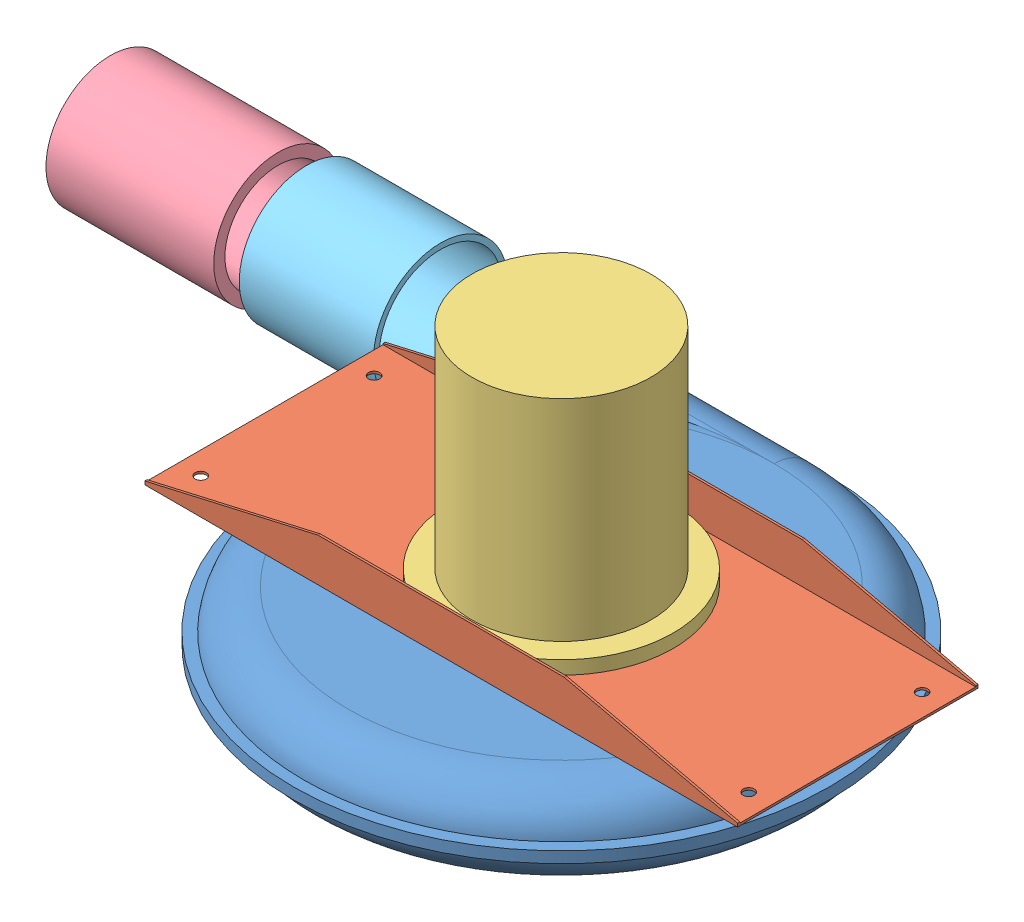
SolidWorks assembly Вытяжка, configuration По умолчанию. Lengths in mm.
Overall size (860.38 326.43 516.43).
5 component instances, 5 part files, 7 mates.
Components (placement in the parent):
- Улитка-1: Улитка [По умолчанию] at origin size (505 110.1 480)
- Крепление-1: Крепление [По умолчанию] at (-265 45 2.5) size (530 38.5 215)
- Мотор-1: Мотор [По умолчанию] at (0 247 0) x (-0.825077 0 -0.56502) z (-0.56502 0 0.825077) size (200 200 200)
- Асбестовая-1: Асбестовая [По умолчанию] at (-595.3778 5 -192) x (0 -0.991749 -0.128194) z (0 -0.128194 0.991749) size (115 150 115)
- Гофра-1: Гофра [По умолчанию] at (-420.0302 5 -192) x (0 -0.774417 -0.632675) z (0 -0.632675 0.774417) size (120 120 120)
Mates (geometry in assembly coordinates):
- Совпадение1: coincident anti-aligned: plane of Улитка-1 through (0 45 0) normal (0 1 0); plane of Крепление-1 through (265 45 107.5) normal (0 -1 0)
- Параллельность1: parallel anti-aligned: plane of Улитка-1 through (-225 10 -155) normal (-1 0 0); plane of Крепление-1 through (265 45 2.5) normal (1 0 0)
- Концентричный3: concentric aligned: cylinder of Асбестовая-1 through (-445.3778 5 -192) axis (-1 0 0) radius 47.5; cylinder of Гофра-1 through (-300.0302 5 -192) axis (-1 0 0) radius 55
- Концентричный4: concentric anti-aligned: cylinder of Улитка-1 through (-265 5 -192) axis (1 0 0) radius 32; cylinder of Гофра-1 through (-300.0302 5 -192) axis (-1 0 0) radius 55
- Концентричный5: concentric aligned: cylinder of Улитка-1 through (0 -65 0) axis (0 1 0) radius 52.5; cylinder of Крепление-1 through (0 45 0) axis (0 1 0) radius 66
- Концентричный6: concentric aligned: cylinder of Крепление-1 through (0 45 0) axis (0 1 0) radius 66; cylinder of Мотор-1 through (0 47 0) axis (0 1 0) radius 100
- Совпадение2: coincident anti-aligned: plane of Крепление-1 through (265 47 107.5) normal (0 1 0); plane of Мотор-1 through (0 47 0) normal (0 -1 0)
